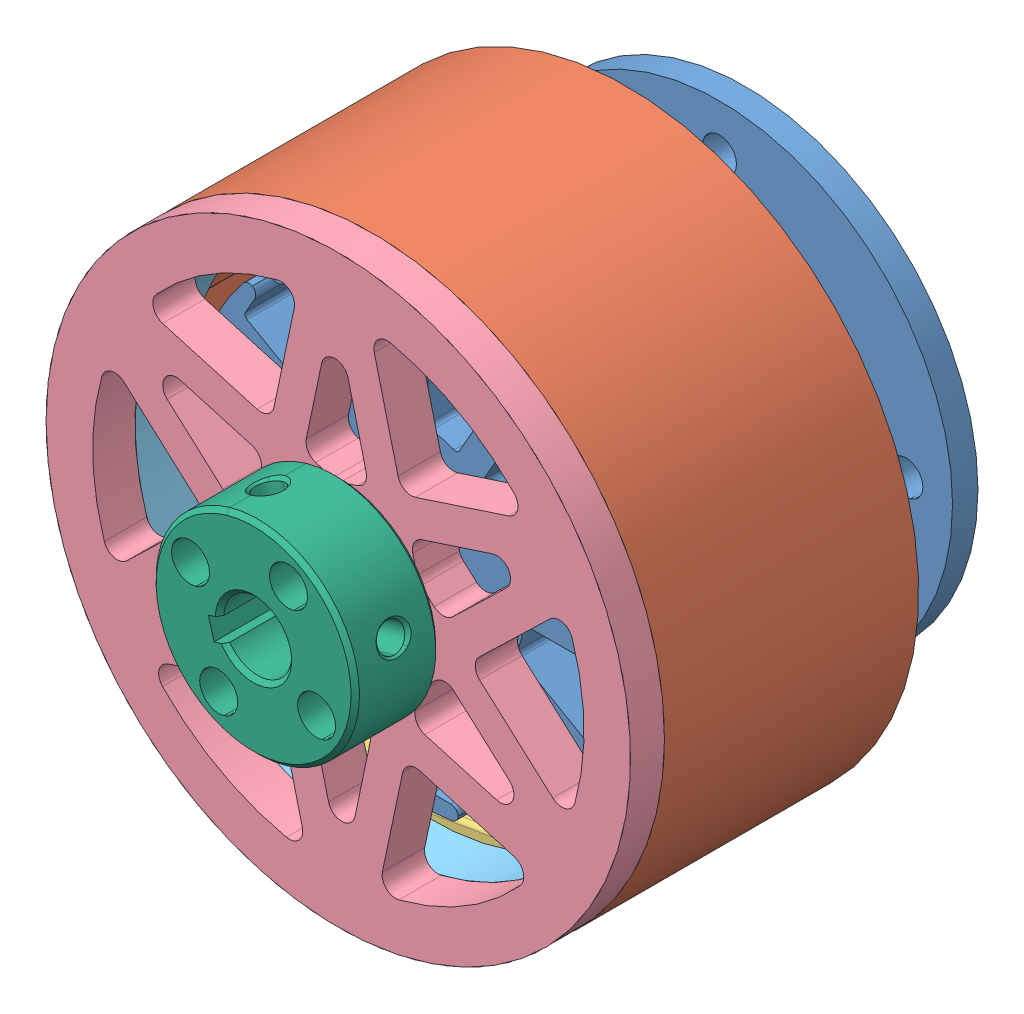
SolidWorks assembly brushless_2nd, configuration ﾃﾞﾌｫﾙﾄ. Lengths in mm.
Overall size (93.78 93.78 58).
10 component instances, 6 part files, 26 mates.
Components (placement in the parent):
- e_power_shin-1: e_power_shin [ﾃﾞﾌｫﾙﾄ] at (11.4846 -0.8322 50) size (55 55 40)
- outer_metal-1: outer_metal [ﾃﾞﾌｫﾙﾄ] at (11.4846 -0.8322 49) x (0.985956 0.167004 0) z (0 0 1) size (69 69 30)
- magnet-1: magnet [ﾃﾞﾌｫﾙﾄ] at (6.8427 26.2732 62) x (0 0 1) z (-0.167004 0.985956 0) size (20 12 5)
- magnet-2: magnet [ﾃﾞﾌｫﾙﾄ] at (19.063 25.603 62) x (0 0 -1) z (0.277325 0.960776 0) size (20 12 5)
- magnet-3: magnet [ﾃﾞﾌｫﾙﾄ] at (16.1266 -27.9377 62) x (0 0 -1) z (0.167004 -0.985956 0) size (20 12 5)
- magnet-4: magnet [ﾃﾞﾌｫﾙﾄ] at (3.9062 -27.2674 62) x (0 0 1) z (-0.277325 -0.960776 0) size (20 12 5)
- plate_al-1: plate_al [ﾃﾞﾌｫﾙﾄ] at (11.4846 -0.8322 83) x (-0.484165 -0.874977 0) z (0 0 -1) size (69 69 5)
- plate_pla-1: plate_pla [ﾃﾞﾌｫﾙﾄ] at (11.4846 -0.8322 68) x (0.745303 -0.666726 0) z (0 0 1) size (65.87 65 6)
- SC_0810CKP4-1: SC_0810CKP4 [Default] at (11.4846 -0.8322 83) x (0 0 1) z (-0.276346 0.961058 0) size (10 24 24)
  - _SC__0810CKP4_2-1: _SC__0810CKP4_2 [Default] at origin size (10 24 24)
Mates (geometry in assembly coordinates):
- 同心円1: concentric: cylinder of e_power_shin-1 through (11.4846 -0.8322 74) axis (0 0 -1) radius 26.25; cylinder of outer_metal-1 through (11.4846 -0.8322 79) axis (0 0 -1) radius 34.5
- 一致1: coincident: plane of outer_metal-1 through (0.092 30.201 49) normal (0.167004 -0.985956 0); plane of magnet-1 through (6.0077 31.203 -3.5987) normal (-0.167004 0.985956 0)
- 平行1: parallel: plane of outer_metal-1 through (11.4846 -0.8322 79) normal (0 0 1); plane of magnet-1 through (0.092 30.201 6.4013) normal (0 0 1)
- 一致3: coincident: plane of outer_metal-1 through (0.426 28.2291 49) normal (0.985956 0.167004 0); plane of magnet-1 through (0.092 30.201 -13.5987) normal (-0.985956 -0.167004 0)
- 一致4: coincident: plane of outer_metal-1 through (14.685 32.0708 49) normal (-0.277325 -0.960776 0); plane of magnet-2 through (20.4497 30.4069 -3.5987) normal (0.277325 0.960776 0)
- 平行2: parallel: plane of outer_metal-1 through (11.4846 -0.8322 79) normal (0 0 1); plane of magnet-2 through (26.2143 28.7429 6.4013) normal (0 0 1)
- 一致6: coincident: plane of outer_metal-1 through (14.1304 30.1493 49) normal (0.960776 -0.277325 0); plane of magnet-2 through (14.685 32.0708 6.4013) normal (-0.960776 0.277325 0)
- 距離1: distance = 5 mm: plane of e_power_shin-1 through (11.4846 -0.8322 74) normal (0 0 1); plane of outer_metal-1 through (11.4846 -0.8322 79) normal (0 0 1)
- 一致8: coincident: plane of outer_metal-1 through (8.2843 -33.7353 49) normal (0.277325 0.960776 0); plane of magnet-4 through (2.5196 -32.0713 -3.5987) normal (-0.277325 -0.960776 0)
- 平行3: parallel: plane of outer_metal-1 through (11.4846 -0.8322 79) normal (0 0 1); plane of magnet-4 through (8.2843 -33.7353 6.4013) normal (0 0 1)
- 一致10: coincident: plane of outer_metal-1 through (8.8389 -31.8137 49) normal (-0.960776 0.277325 0); plane of magnet-4 through (8.2843 -33.7353 -13.5987) normal (0.960776 -0.277325 0)
- 一致11: coincident: plane of outer_metal-1 through (22.8773 -31.8654 49) normal (-0.167004 0.985956 0); plane of magnet-3 through (16.9616 -32.8674 -3.5987) normal (0.167004 -0.985956 0)
- 一致12: coincident: plane of outer_metal-1 through (22.5433 -29.8935 49) normal (-0.985956 -0.167004 0); plane of magnet-3 through (22.8773 -31.8654 6.4013) normal (0.985956 0.167004 0)
- 一致13: coincident: plane of outer_metal-1 through (11.4846 -0.8322 79) normal (0 0 1); plane of plate_al-1 through (11.4846 -0.8322 79) normal (0 0 -1)
- 一致14: coincident: plane of outer_metal-1 through (-12.2446 22.1846 49) normal (0.578256 -0.815856 0); plane of plate_al-1 through (-2.3727 29.1815 78) normal (-0.578256 0.815856 0)
- 同心円2: concentric: cylinder of outer_metal-1 through (11.4846 -0.8322 79) axis (0 0 -1) radius 34.5; cylinder of plate_al-1 through (11.4846 -0.8322 79) axis (0 0 1) radius 34.5
- 一致19: coincident: plane of magnet-3 through (11.0458 -33.8695 -13.5987) normal (0 0 -1); plane of magnet-4 through (8.2843 -33.7353 -13.5987) normal (0 0 -1)
- 一致20: coincident: plane of magnet-1 through (0.092 30.201 -13.5987) normal (0 0 -1); plane of magnet-4 through (8.2843 -33.7353 -13.5987) normal (0 0 -1)
- 一致21: coincident: plane of magnet-1 through (0.092 30.201 -13.5987) normal (0 0 -1); plane of magnet-2 through (26.2143 28.7429 -13.5987) normal (0 0 -1)
- 一致22: coincident: plane of outer_metal-1 through (44.2749 3.3693 49) normal (-0.998398 0.056579 0); plane of plate_pla-1 through (44.2749 3.3693 9.4013) normal (0.998398 -0.056579 0)
- 同心円3: concentric: circle of outer_metal-1; circle of plate_pla-1
- 一致24: coincident: plane of magnet-4 through (8.2843 -33.7353 6.4013) normal (0 0 1); plane of plate_pla-1 through (11.4846 -0.8322 6.4013) normal (0 0 -1)
- 同心円4: concentric: circle of plate_al-1; circle of SC_0810CKP4-1/_SC__0810CKP4_2-1
- 一致25: coincident: plane of plate_al-1 through (11.4846 -0.8322 83) normal (0 0 1); plane of SC_0810CKP4-1/_SC__0810CKP4_2-1 through (22.5368 2.3458 83) normal (0 0 -1)
- 同心円5: concentric: circle of plate_al-1; circle of SC_0810CKP4-1/_SC__0810CKP4_2-1
- 一致26: coincident: plane of plate_al-1 through (11.4846 -0.8322 78) normal (0 0 -1); plane of plate_pla-1 through (-20.207 -7.9344 78) normal (0 0 1)
